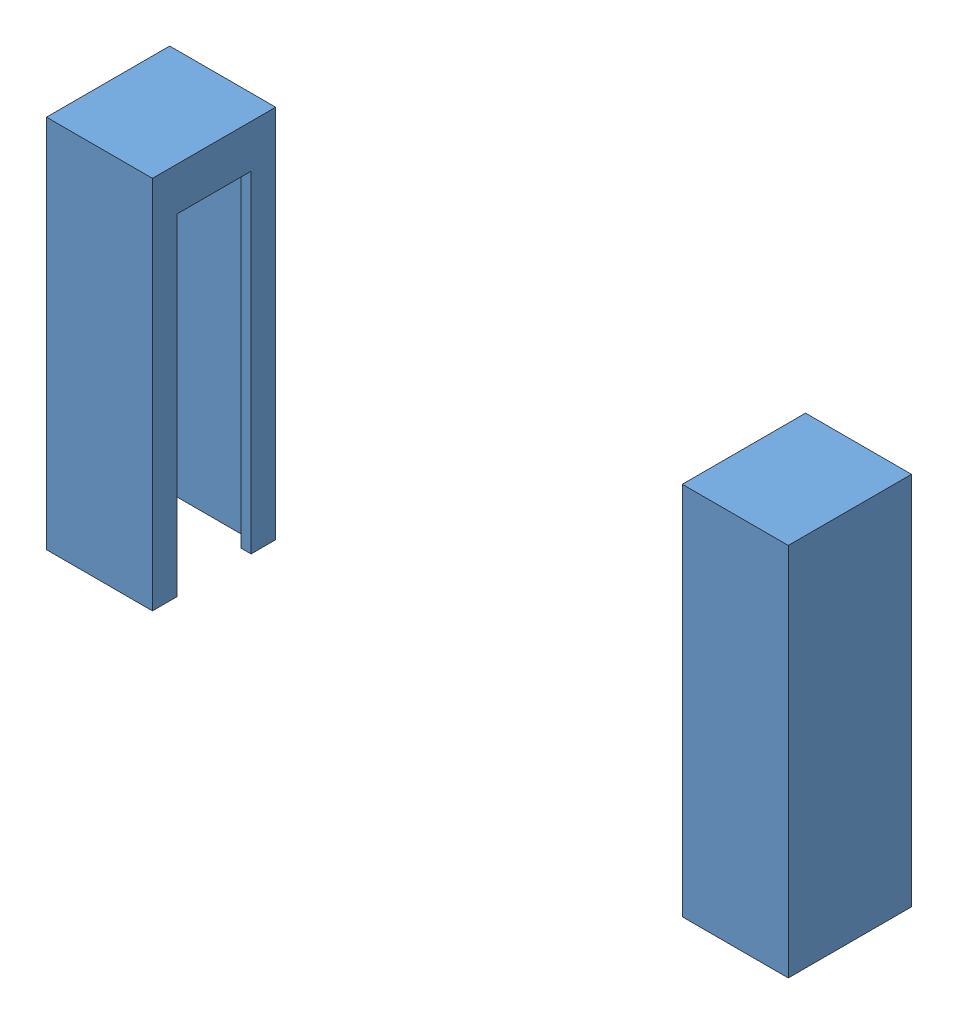
SolidWorks assembly preferenceV2_dispenser_IRAssembly - Copy, configuration Default. Lengths in mm.
Overall size (30.1 15.2 5).
4 component instances, 1 part files, 3 mates.
Components (placement in the parent):
- sparkfunIR_LEDandCase-1: sparkfunIR_LEDandCase [2Pin] at (-11.0025 21.2786 44.4241) x (-1 0 0) z (0 0 -1) size (4.3 15.2 5)
  - sparkfunIR_casing-1: sparkfunIR_casing [Default] at (-40.6525 -5.8286 32.4491) x (1 0 0) z (0 0 -1) size (4.3 15.2 5)
- sparkfunIR_LEDandCase-2: sparkfunIR_LEDandCase [3Pin] at (44.5025 21.2786 -20.4741) size (4.3 15.2 5)
  - sparkfunIR_casing-1: sparkfunIR_casing [Default] at (-40.6525 -5.8286 32.4491) x (1 0 0) z (0 0 -1) size (4.3 15.2 5)
Mates (geometry in assembly coordinates):
- Distance1: distance = 30.1 mm anti-aligned: plane of sparkfunIR_LEDandCase-2/sparkfunIR_casing-1 through (1.7 15.45 9.475) normal (-1 0 0); plane of sparkfunIR_LEDandCase-1/sparkfunIR_casing-1 through (31.8 15.45 14.475) normal (1 0 0)
- Coincident2: coincident aligned: plane of sparkfunIR_LEDandCase-1/sparkfunIR_casing-1 through (29.65 15.45 14.475) normal (0 0 1); plane of sparkfunIR_LEDandCase-2/sparkfunIR_casing-1 through (5.45 15.45 14.475) normal (0 0 1)
- Coincident3: coincident aligned: plane of sparkfunIR_LEDandCase-1/sparkfunIR_casing-1 through (31.8 0.25 14.475) normal (0 -1 0); plane of sparkfunIR_LEDandCase-2/sparkfunIR_casing-1 through (3.3 0.25 9.475) normal (0 -1 0)
